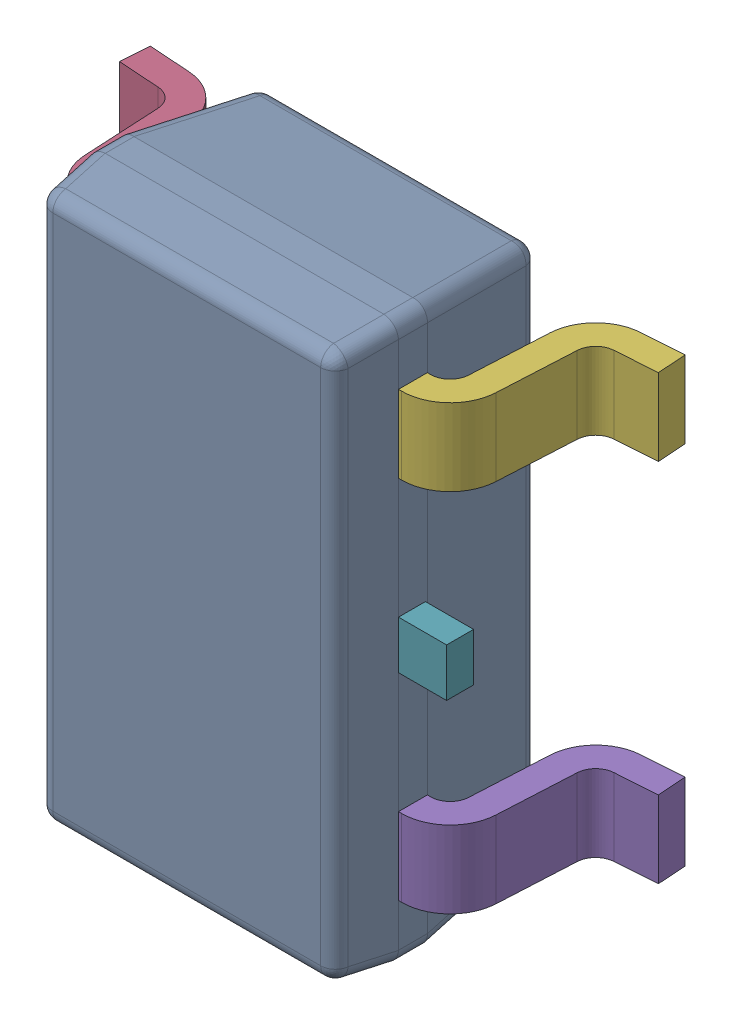
SolidWorks assembly 6348794768_1.step, configuration Default. Lengths in mm.
Overall size (2.8 2.9 1.2).
7 component instances, 3 part files, 0 mates.
Components (placement in the parent):
- BODY-SOT-9_1.step-3: BODY-SOT-9_1.step [Default] at (0 0 0.9) x (0 -1 0) z (-1 0 0) size (2.9 1.1 1.6)
- LEAD-SOT-10_1.step-13: LEAD-SOT-10_1.step [Default] at (-0.9395 -0.95 0.25) x (0 -1 0) z (-1 0 0) size (0.4 0.9 0.6)
- LEAD-SOT-10_1.step-14: LEAD-SOT-10_1.step [Default] at (-0.9395 0 0.25) x (0 -1 0) z (-1 0 0) size (0.4 0.9 0.6)
- LEAD-SOT-10_1.step-15: LEAD-SOT-10_1.step [Default] at (-0.9395 0.95 0.25) x (0 -1 0) z (-1 0 0) size (0.4 0.9 0.6)
- LEAD-SOT-10_1.step-16: LEAD-SOT-10_1.step [Default] at (0.9395 -0.95 0.25) x (0 1 0) z (1 0 0) size (0.4 0.9 0.6)
- LEAD-SOT-10_1.step-17: LEAD-SOT-10_1.step [Default] at (0.9395 0.95 0.25) x (0 1 0) z (1 0 0) size (0.4 0.9 0.6)
- LEAD-DUMMY-11_1.step-3: LEAD-DUMMY-11_1.step [Default] at (1.05 0 0.76) x (0 -1 0) z (-1 0 0) size (0.25 0.14 0.25)
